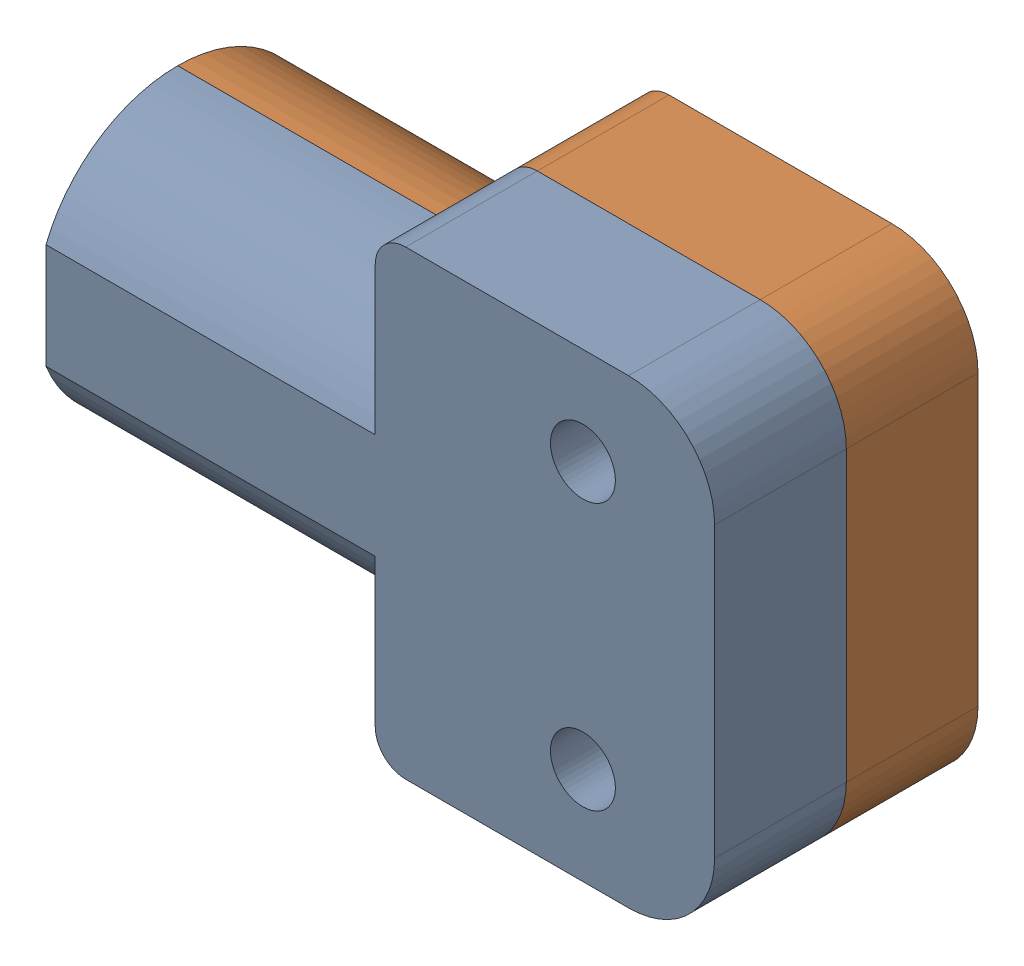
SolidWorks assembly MFG CW Pedal Mount Block Assembly_1, configuration Default. Lengths in mm.
Overall size (66 45.5 26).
4 component instances, 3 part files, 0 mates.
Components (placement in the parent):
- MFG CW Pedal Mount Block Upper-1: MFG CW Pedal Mount Block Upper [Default] at origin size (66 45.5 13)
- MFG CW Pedal Mount Block Lower-1: MFG CW Pedal Mount Block Lower [Default] at origin size (66 45.5 13)
- M6 x 1 Hex Nut-1: M6 x 1 Hex Nut [Default] at (177 95.845 88.6) size (10 11.55 5)
- M6 x 1 Hex Nut-2: M6 x 1 Hex Nut [Default] at (177 122.155 88.6) size (10 11.55 5)
